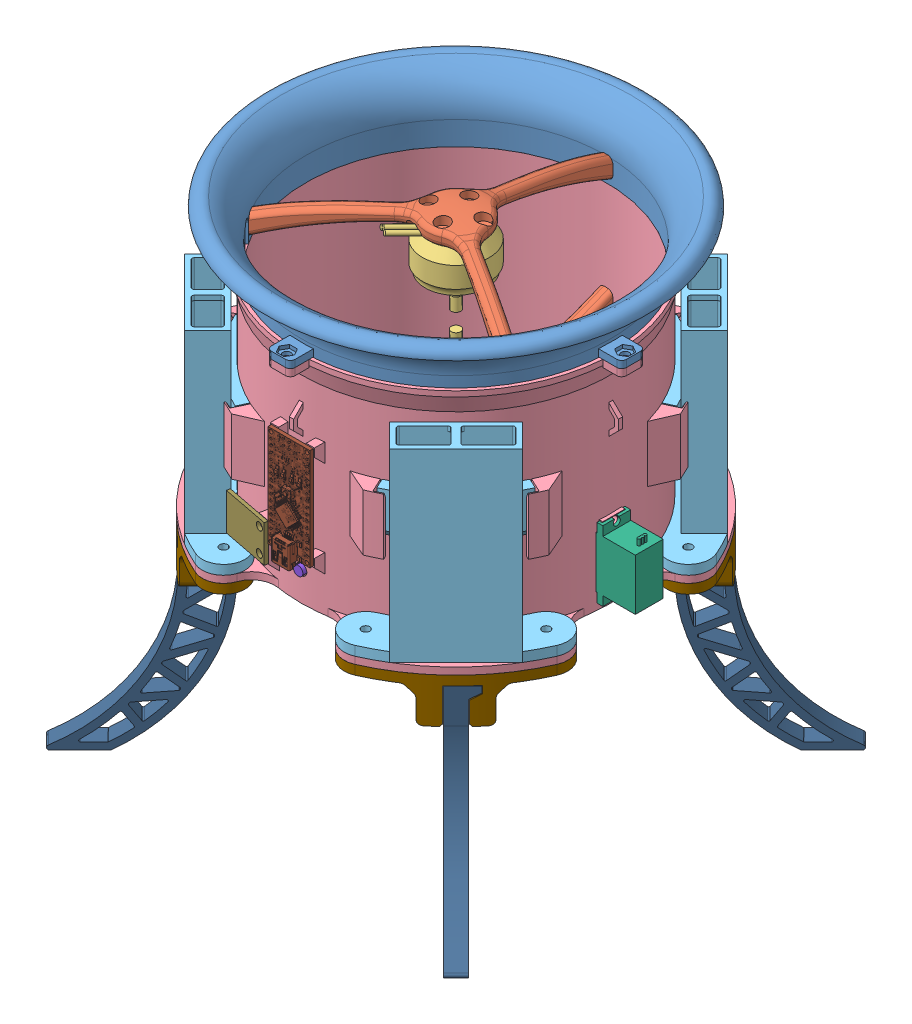
SolidWorks assembly Drone Duct Assembly v10.2, configuration Default. Lengths in mm.
Overall size (179.25 201.56 179.25).
26 component instances, 12 part files, 42 mates.
Components (placement in the parent):
- Propeller Duct 5inch Top-1: Propeller Duct 5inch Top [Default] at origin size (160.85 27.31 160.85)
- Motor Bracket v3-1: Motor Bracket v3 [Default] at (0 12.5985 0) size (121.04 20.92 107.21)
- T-motor Latest F40III KV2400 FPV Racing Motor Screw Shaft-2: T-motor Latest F40III KV2400 FPV Racing Motor Screw Shaft [Default] at (0 31.0985 0) x (-0.258819 0 -0.965926) z (-0.965926 0 0.258819) size (32.32 35.07 32.24)
- Propeller Duct 5inch Bottom-1: Propeller Duct 5inch Bottom [Default] at (0 15.0985 0) x (-1 0 0) z (0 0 -1) size (155.23 93 155.23)
- Motor Bracket v3-2: Motor Bracket v3 [Default] at (0 -18.9015 0) x (0.5 0 -0.866025) z (-0.866025 0 -0.5) size (121.04 20.92 107.21)
- T-motor Latest F40III KV2400 FPV Racing Motor Screw Shaft-1: T-motor Latest F40III KV2400 FPV Racing Motor Screw Shaft [Default] at (0 -37.4015 0) x (0.707107 0 0.707107) z (-0.707107 0 0.707107) size (32.32 35.07 32.24)
- BatteryEnclosureBolted-1: BatteryEnclosureBolted [Default] at (36.4514 -71.9015 -61.9072) x (0.707107 0 0.707107) z (-0.707107 0 0.707107) size (72.43 78.5 20.88)
- mksS311 Digital Servo-2: mksS311 Digital Servo [Default] at (68.2958 -57.0065 0) x (0 0 -1) z (0 1 0) size (11.85 26.1 29.7)
- mksS311 arm attachment-1: mksS311 arm attachment [Default] at (54.7958 -51.6065 0) x (0 0.012151 -0.999926) z (0 -0.999926 -0.012151) size (18 4 29)
- flap v1-1: flap v1 [Default] at (52.9958 -51.6065 0) x (0 0.012151 -0.999926) z (0 -0.999926 -0.012151) size (18 121.8 29)
- flap v1-4: flap v1 [Default] at (0 -62.4065 -53) x (-0.981327 0.192346 0) z (-0.192346 -0.981327 0) size (18 121.8 29)
- mksS311 Digital Servo-4: mksS311 Digital Servo [Default] at (0 -57.0065 -68.3) x (1 0 0) z (0 -1 0) size (11.85 26.1 29.7)
- mksS311 arm attachment-3: mksS311 arm attachment [Default] at (0 -62.4065 -54.8) x (-0.981327 0.192346 0) z (-0.192346 -0.981327 0) size (18 4 29)
- BatteryEnclosureBolted-2: BatteryEnclosureBolted [Default] at (61.9072 -71.9015 36.4514) x (-0.707107 0 0.707107) z (-0.707107 0 -0.707107) size (72.43 78.5 20.88)
- BatteryEnclosureBolted-3: BatteryEnclosureBolted [Default] at (-36.4514 -71.9015 61.9072) x (-0.707107 0 -0.707107) z (0.707107 0 -0.707107) size (72.43 78.5 20.88)
- BatteryEnclosureBolted-4: BatteryEnclosureBolted [Default] at (-61.9072 -71.9015 -36.4514) x (0.707107 0 -0.707107) z (0.707107 0 0.707107) size (72.43 78.5 20.88)
- Leg Clip-1: Leg Clip [Default] at origin size (56.55 19.12 56.55)
- Leg-1: Leg [Default] at origin size (48.69 80 45.86)
- Leg Clip-2: Leg Clip [Default] x (0 0 1) z (-1 0 0) size (56.55 19.12 56.55)
- Leg Clip-3: Leg Clip [Default] x (-1 0 0) z (0 0 -1) size (56.55 19.12 56.55)
- Leg Clip-4: Leg Clip [Default] x (0 0 -1) z (1 0 0) size (56.55 19.12 56.55)
- Leg-2: Leg [Default] x (0 0 1) z (-1 0 0) size (48.69 80 45.86)
- Leg-3: Leg [Default] x (-1 0 0) z (0 0 -1) size (48.69 80 45.86)
- Leg-4: Leg [Default] x (0 0 -1) z (1 0 0) size (48.69 80 45.86)
- Arduino Nano-1: Arduino Nano [Default] at (-7.62 -15.5315 61.48) x (0 1 0) z (0 0 1) size (44.99 17.78 7.35)
- Gy-61 gyro board-1: Gy-61 gyro board [Default] at (-21.0879 -56.4015 68.3953) x (0 1 0) z (-0.981627 0 -0.190809) size (15.7 1.46 20.3)
Mates (geometry in assembly coordinates):
- Concentric1: concentric aligned: cylinder of Propeller Duct 5inch Top-1 through (0 0 0) axis (0 -1 0) radius 63.75; cylinder of Motor Bracket v3-1 through (0 12.5985 0) axis (0 -1 0) radius 63.75
- Concentric2: concentric aligned: cylinder of Propeller Duct 5inch Top-1 through (0 0 0) axis (0 -1 0) radius 63.75; cylinder of T-motor Latest F40III KV2400 FPV Racing Motor Screw Shaft-2 through (0 0.5985 0) axis (0 -1 0) radius 14.2
- Concentric3: concentric aligned: cylinder of Motor Bracket v3-1 through (-9.1763 34.0985 2.4588) axis (0 1 0) radius 1.7; cylinder of T-motor Latest F40III KV2400 FPV Racing Motor Screw Shaft-2 through (-9.1763 31.0985 2.4588) axis (0 1 0) radius 1.25
- Concentric4: concentric aligned: cylinder of Motor Bracket v3-1 through (2.0706 34.0985 7.7274) axis (0 1 0) radius 1.7; cylinder of T-motor Latest F40III KV2400 FPV Racing Motor Screw Shaft-2 through (2.0706 31.0985 7.7274) axis (0 1 0) radius 1.25
- Concentric5: concentric aligned: cylinder of Propeller Duct 5inch Top-1 through (0 0 0) axis (0 -1 0) radius 65.75; cylinder of Propeller Duct 5inch Bottom-1 through (0 15.0985 0) axis (0 -1 0) radius 65.75
- Distance1: distance = 2.5 mm anti-aligned: plane of Motor Bracket v3-1 through (0 12.5985 0) normal (0 1 0); plane of Propeller Duct 5inch Top-1 through (63.75 15.0985 0) normal (0 -1 0)
- Concentric7: concentric anti-aligned: cylinder of Propeller Duct 5inch Bottom-1 through (0 15.0985 0) axis (0 -1 0) radius 63.75; cylinder of Motor Bracket v3-2 through (0 -18.9015 0) axis (0 1 0) radius 63.75
- Distance2: distance = 52.5 mm aligned: plane of Propeller Duct 5inch Bottom-1 through (0 15.0985 0) normal (0 1 0); plane of Motor Bracket v3-2 through (0 -37.4015 0) normal (0 1 0)
- Concentric8: concentric anti-aligned: cylinder of Propeller Duct 5inch Bottom-1 through (0 15.0985 0) axis (0 -1 0) radius 63.75; cylinder of T-motor Latest F40III KV2400 FPV Racing Motor Screw Shaft-1 through (0 -6.9015 0) axis (0 1 0) radius 14.2
- Concentric9: concentric aligned: cylinder of Motor Bracket v3-2 through (-6.7175 -40.4015 6.7175) axis (0 -1 0) radius 1.7; cylinder of T-motor Latest F40III KV2400 FPV Racing Motor Screw Shaft-1 through (-6.7175 -37.4015 6.7175) axis (0 -1 0) radius 1.25
- Concentric10: concentric aligned: cylinder of Motor Bracket v3-2 through (-5.6569 -40.4015 -5.6569) axis (0 -1 0) radius 1.7; cylinder of T-motor Latest F40III KV2400 FPV Racing Motor Screw Shaft-1 through (-5.6569 -37.4015 -5.6569) axis (0 -1 0) radius 1.25
- Coincident5: coincident anti-aligned: plane of Motor Bracket v3-2 through (0 -37.4015 0) normal (0 1 0); plane of T-motor Latest F40III KV2400 FPV Racing Motor Screw Shaft-1 through (7.9903 -37.4015 7.9903) normal (0 -1 0)
- Coincident6: coincident anti-aligned: plane of Propeller Duct 5inch Top-1 through (63.75 15.0985 0) normal (0 -1 0); plane of Propeller Duct 5inch Bottom-1 through (-63.75 15.0985 0) normal (0 1 0)
- Coincident7: coincident aligned: plane of Motor Bracket v3-1 through (0 12.5985 0) normal (0 0 1); plane of assembly through (0 0 0) normal (0 0 1)
- Angle2: planar angle = 2.094395 rad aligned: plane of Motor Bracket v3-2 through (0 -18.9015 0) normal (-0.866025 0 -0.5); plane of assembly through (0 0 0) normal (0 0 1)
- Coincident9: coincident anti-aligned: plane of Propeller Duct 5inch Top-1 through (0 0 0) normal (0 0 1); plane of Propeller Duct 5inch Bottom-1 through (0 15.0985 0) normal (0 0 -1)
- Coincident10: coincident anti-aligned: plane of Motor Bracket v3-1 through (0 31.0985 0) normal (0 -1 0); plane of T-motor Latest F40III KV2400 FPV Racing Motor Screw Shaft-2 through (-2.9247 31.0985 -10.915) normal (0 1 0)
- Concentric11: concentric anti-aligned: cylinder of Propeller Duct 5inch Top-1 through (0 0 0) axis (0 -1 0) radius 65.75; cylinder of BatteryEnclosureBolted-1 through (0 -38.4015 0) axis (0 1 0) radius 65.75
- Concentric12: concentric aligned: circle of mksS311 Digital Servo-2; circle of mksS311 arm attachment-1
- Coincident14: coincident anti-aligned: plane of mksS311 Digital Servo-2 through (55.9958 -57.0065 0) normal (-1 0 0); plane of mksS311 arm attachment-1 through (55.9958 -51.6065 0) normal (1 0 0)
- Coincident29: coincident aligned: circle of mksS311 arm attachment-1; circle of flap v1-1
- Coincident30: coincident aligned: circle of mksS311 arm attachment-1; circle of flap v1-1
- Concentric14: concentric aligned: cylinder of Propeller Duct 5inch Bottom-1 through (0 -70.3615 -280) axis (0 0 1) radius 1.5; cylinder of mksS311 Digital Servo-4 through (0 -70.3615 -68.3) axis (0 0 1) radius 1.5
- Concentric15: concentric aligned: cylinder of Propeller Duct 5inch Bottom-1 through (0 -43.6515 -280) axis (0 0 1) radius 1.5; cylinder of mksS311 Digital Servo-4 through (0 -43.6515 -68.3) axis (0 0 1) radius 1.5
- Coincident31: coincident anti-aligned: plane of Propeller Duct 5inch Bottom-1 through (0 15.0985 -67.1) normal (0 0 -1); plane of mksS311 Digital Servo-4 through (0 -57.0065 -67.1) normal (0 0 1)
- Concentric16: concentric aligned: cylinder of mksS311 Digital Servo-4 through (0 -62.4065 -23.0552) axis (0 0 -1) radius 2.42; cylinder of mksS311 arm attachment-3 through (0 -62.4065 -56) axis (0 0 -1) radius 2.425
- Coincident32: coincident anti-aligned: plane of mksS311 Digital Servo-4 through (0 -57.0065 -56) normal (0 0 1); plane of mksS311 arm attachment-3 through (0 -62.4065 -56) normal (0 0 -1)
- Coincident33: coincident anti-aligned: plane of flap v1-4 through (6.8693 -63.7529 -54.8) normal (0 0 -1); plane of mksS311 arm attachment-3 through (6.8693 -63.7529 -54.8) normal (0 0 1)
- Concentric21: concentric aligned: cylinder of flap v1-4 through (-2.4043 -74.6731 -53) axis (0 0 -1) radius 0.5; cylinder of mksS311 arm attachment-3 through (-2.4043 -74.6731 -54.8) axis (0 0 -1) radius 0.5
- Concentric22: concentric aligned: cylinder of flap v1-4 through (2.4043 -50.1399 -53) axis (0 0 -1) radius 0.5; cylinder of mksS311 arm attachment-3 through (2.4043 -50.1399 -54.8) axis (0 0 -1) radius 0.5
- Concentric23: concentric anti-aligned: cylinder of Propeller Duct 5inch Bottom-1 through (59.5958 -43.6515 0) axis (1 0 0) radius 1.5; cylinder of mksS311 Digital Servo-2 through (68.2958 -43.6515 0) axis (-1 0 0) radius 1.5
- Concentric24: concentric anti-aligned: cylinder of Propeller Duct 5inch Bottom-1 through (59.5958 -70.3615 0) axis (1 0 0) radius 1.5; cylinder of mksS311 Digital Servo-2 through (68.2958 -70.3615 0) axis (-1 0 0) radius 1.5
- Coincident37: coincident anti-aligned: plane of Propeller Duct 5inch Bottom-1 through (67.0958 15.0985 0) normal (1 0 0); plane of mksS311 Digital Servo-2 through (67.0958 -57.0065 0) normal (-1 0 0)
- Concentric25: concentric aligned: cylinder of Propeller Duct 5inch Bottom-1 through (30.1717 -71.9015 -68.5087) axis (0 -1 0) radius 1.7; cylinder of BatteryEnclosureBolted-1 through (30.1717 -67.9015 -68.5087) axis (0 -1 0) radius 1.7
- Coincident38: coincident anti-aligned: plane of Propeller Duct 5inch Bottom-1 through (0 -71.9015 0) normal (0 1 0); plane of BatteryEnclosureBolted-1 through (36.4514 -71.9015 -61.9072) normal (0 -1 0)
- Parallel1: parallel anti-aligned: plane of Arduino Nano-1 through (-8.89 -54.9015 70.96) normal (0 -1 0); plane of assembly through (0 0 0) normal (0 1 0)
- Distance3: distance = 20 mm aligned: plane of Arduino Nano-1 through (-8.89 -54.9015 70.96) normal (0 -1 0); plane of Propeller Duct 5inch Bottom-1 through (-63.75 -74.9015 0) normal (0 -1 0)
- Symmetric1: symmetric aligned: plane of Arduino Nano-1 through (8.89 -54.9015 70.96) normal (1 0 0); plane of Arduino Nano-1 through (-8.89 -11.7215 70.96) normal (-1 0 0); plane of assembly through (0 0 0) normal (1 0 0)
- Coincident41: coincident anti-aligned: plane of Propeller Duct 5inch Bottom-1 through (0 15.0985 69.5) normal (0 0 1); plane of Arduino Nano-1 through (0 -33.3115 69.5) normal (0 0 -1)
- Coincident45: coincident anti-aligned: plane of Propeller Duct 5inch Bottom-1 through (-10.8458 -68.4015 68.8988) normal (-0.190809 0 0.981627); plane of Gy-61 gyro board-1 through (-20.8093 -56.4015 66.9621) normal (0.190809 0 -0.981627)
- Coincident46: coincident anti-aligned: line of Propeller Duct 5inch Bottom-1 through (-10.8458 -64.4015 68.8988) axis (0 1 0); line of Gy-61 gyro board-1 through (-10.8458 -48.5515 68.8988) axis (0 -1 0)
- Coincident48: coincident: point of Propeller Duct 5inch Bottom-1; unknown of Gy-61 gyro board-1
